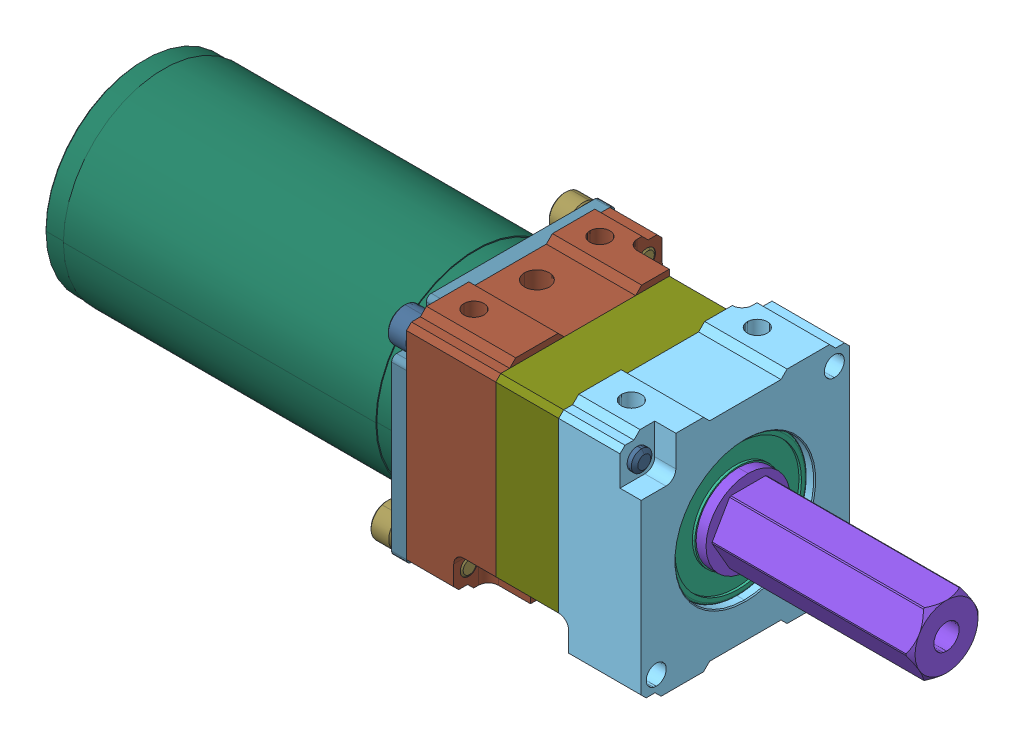
SolidWorks assembly VersaPlanetary_v2_Single_Stage_10_1_with_BAG, configuration Default. Lengths in mm.
Overall size (163.4 63.52 63.52).
30 component instances, 19 part files, 0 mates.
Components (placement in the parent):
- VersaPlanetary_v2_Single_Stage_10_1_with_BAG.STEP-1: VersaPlanetary_v2_Single_Stage_10_1_with_BAG.STEP [Default] at origin size (163.4 63.52 63.52)
  - 217-2820 Rev1_Public.STEP-1: 217-2820 Rev1_Public.STEP [Default] at (-4.6546 22.225 0) x (0 -0.456494 0.889726) z (-1 0 0) size (39.22 38.88 17.4)
    - 217-2625-100.STEP-1: 217-2625-100.STEP [Default] at origin size (39.22 38.88 12.7)
      - 217-2625-008 Rev1.STEP-1: 217-2625-008 Rev1.STEP [Default] at origin size (34.7 34.7 4.7)
      - 217-2625-010 Rev1.STEP-1: 217-2625-010 Rev1.STEP [Default] at (0 10.193 3.65) x (0.999813 0.019336 0) z (0 0 1) size (4 4 12)
      - 217-2625-010 Rev1.STEP-2: 217-2625-010 Rev1.STEP [Default] at (8.691 -5.3258 3.65) size (4 4 12)
      - 217-2625-010 Rev1.STEP-3: 217-2625-010 Rev1.STEP [Default] at (-8.691 -5.3258 3.65) size (4 4 12)
      - 217-2625-005 Rev1_Planet_Revolving_Follower01.STEP-1: 217-2625-005 Rev1_Planet_Revolving_Follower01.STEP [Default] at (8.691 -5.3258 6.35) x (0.932816 0.360354 0) z (0 0 1) size (16.89 16.89 8)
      - 217-2625-005 Rev1_Planet_Revolving_Follower01.STEP-2: 217-2625-005 Rev1_Planet_Revolving_Follower01.STEP [Default] at (-8.691 -5.3258 6.35) x (-0.932788 -0.360426 0) z (0 0 1) size (16.89 16.89 8)
      - 217-2625-005 Rev1_Planet_Revolving_Follower01.STEP-3: 217-2625-005 Rev1_Planet_Revolving_Follower01.STEP [Default] at (0 10.193 6.35) x (0.893583 0.448898 0) z (0 0 1) size (16.89 16.89 8)
    - 217-2625-007 Rev1_Public.STEP-1: 217-2625-007 Rev1_Public.STEP [Default] at (0 0 6.7) x (0.992772 0.120019 0) z (0 0 1) size (15.27 15.27 12.7)
  - 217-2625-026 Rev1.STEP-1: 217-2625-026 Rev1.STEP [Default] at (-6.5 22.225 0) x (0 -1 0) z (-1 0 0) size (44.45 42 18.12)
  - 217-2742-001 Rev4.STEP-1: 217-2742-001 Rev4.STEP [Default] at (0.2002 22.225 0) x (1 0 0) z (0 -0.092627 0.995701) size (7 28 28)
  - 217-2742-001 Rev4.STEP-2: 217-2742-001 Rev4.STEP [Default] at (8.2002 22.225 0) size (7 28 28)
  - 217-2625-017 Rev1_9714K61.STEP-1: 217-2625-017 Rev1_9714K61.STEP [Default] at (7.42 22.3002 -0.342) x (0 0.56703 0.823697) z (0 -0.823697 0.56703) size (28.51 4.98 27.43)
  - 217-2625-003 Rev1.STEP-1: 217-2625-003 Rev1.STEP [Default] at (7.4478 22.225 0) x (0 -1 0) z (1 0 0) size (17 17 64.11)
  - 217-2625-018 Rev1_98541A410.STEP-1: 217-2625-018 Rev1_98541A410.STEP [Default] at (-0.7046 22.225 0) x (1 0 0) z (0 -0.017452 0.999848) size (1 19.6 17.4)
  - 832-1750-Ring-Gear-Screw_SSA0832-0500ZC.STEP-1: 832-1750-Ring-Gear-Screw_SSA0832-0500ZC.STEP [Default] at (-30.7 4.725 -17.5) x (0 0.997447 0.071411) z (0 -0.071411 0.997447) size (6.73 48.51 6.73)
  - 832-1750-Ring-Gear-Screw_SSA0832-0500ZC.STEP-2: 832-1750-Ring-Gear-Screw_SSA0832-0500ZC.STEP [Default] at (-30.7 39.725 17.5) x (0 0.005929 0.999982) z (0 -0.999982 0.005929) size (6.73 48.51 6.73)
  - 217-2625-025 Rev1.STEP-1: 217-2625-025 Rev1.STEP [Default] at (-23.2 22.225 0) x (0 -1 0) z (-1 0 0) size (44.45 42 18)
  - 217-4649-002 Rev1_SSA0832-0500ZC.STEP-1: 217-4649-002 Rev1_SSA0832-0500ZC.STEP [Default] at (-33.7 4.2645 17.9605) x (0 0.33842 -0.940995) z (0 0.940995 0.33842) size (6.73 16.76 6.73)
  - 217-4649-002 Rev1_SSA0832-0500ZC.STEP-2: 217-4649-002 Rev1_SSA0832-0500ZC.STEP [Default] at (-33.7 40.1855 -17.9605) x (0 -0.308932 -0.951084) z (0 0.951084 -0.308932) size (6.73 16.76 6.73)
  - 217-4649-006 Rev1_SSA0004-008BA.STEP-1: 217-4649-006 Rev1_SSA0004-008BA.STEP [Default] at (-30.7 22.225 12.5) x (0 0.5 -0.866025) z (0 -0.866025 -0.5) size (7 14 7)
  - 217-4649-006 Rev1_SSA0004-008BA.STEP-2: 217-4649-006 Rev1_SSA0004-008BA.STEP [Default] at (-30.7 22.225 -12.5) x (0 -0.5 0.866025) z (0 0.866025 0.5) size (7 14 7)
  - 217-2822-003 Rev4.STEP-1: 217-2822-003 Rev4.STEP [Default] at (-32.2 22.225 0) x (0 -1 0) z (-1 0 0) size (42 42 4.8)
  - 217-3351 Rev2.STEP-1: 217-3351 Rev2.STEP [Default] at (-33.7 22.225 0) x (0 0 1) z (1 0 0) size (59.07 59.07 84.5)
  - 217-2816-001 Rev1.STEP-1: 217-2816-001 Rev1.STEP [Default] at (-6.35 22.225 0) x (0 -1 0) z (1 0 0) size (42 42 14.51)
  - 217-4649-001 Rev1.STEP-1: 217-4649-001 Rev1.STEP [Default] at (-20.046 22.225 0) x (0 -1 0) z (1 0 0) size (18 18 13)
  - 217-4649-007 Rev1_94105A824.STEP-1: 217-4649-007 Rev1_94105A824.STEP [Default] at (-25.521 22.225 -6.7835) x (-0.996104 -0.088191 0) z (0 0 -1) size (4.83 4.83 4.77)
  - 217-2625-011 Rev1.STEP-1: 217-2625-011 Rev1.STEP [Default] at (-24.7818 22.225 0) x (0 0 1) z (0 -1 0) size (8.01 7.5 7.94)
